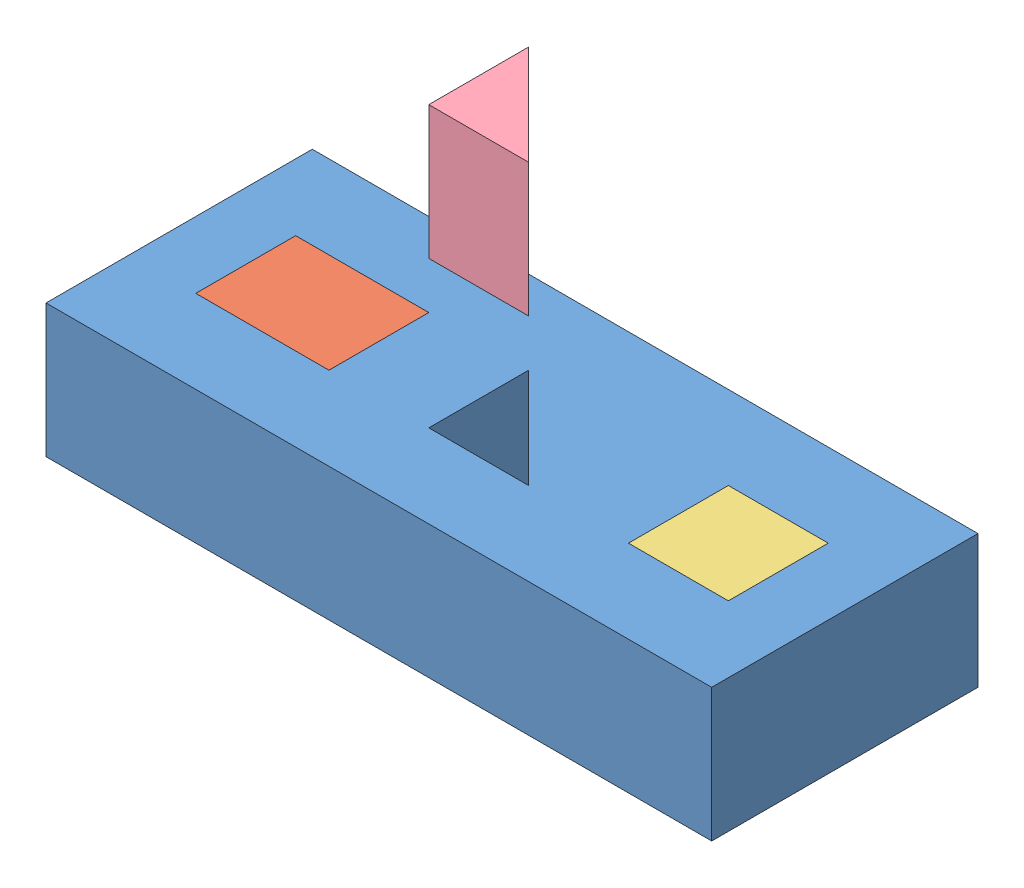
SolidWorks assembly Assembly 61, configuration Default. Lengths in mm.
Overall size (127 78.8 50.8).
4 component instances, 4 part files, 8 mates.
Components (placement in the parent):
- Block_Coinc_parallel_prepend_2013-2: Block_Coinc_parallel_prepend_2013 [Default] at (-15.2145 52.4167 123.2064) size (127 25.4 50.8)
- rectangle_1_2013-2: rectangle_1_2013 [Default] at (-2.5145 52.4167 107.3314) size (25.4 25.4 19.05)
- Square_2013-2: Square_2013 [Default] at (80.0355 52.4167 107.3314) size (19.05 25.4 19.05)
- Traingle_2013-2: Traingle_2013 [Default] at (41.9355 105.8179 107.3314) size (19.05 25.4 19.05)
Mates (geometry in assembly coordinates):
- Coincident11: coincident: point of Block_Coinc_parallel_prepend_2013-2; point of rectangle_1_2013-2
- Coincident12: coincident: point of Block_Coinc_parallel_prepend_2013-2; point of rectangle_1_2013-2
- Coincident13: coincident aligned: plane of Block_Coinc_parallel_prepend_2013-2 through (-15.2145 77.8167 123.2064) normal (0 1 0); plane of rectangle_1_2013-2 through (-2.5145 77.8167 107.3314) normal (0 1 0)
- Perpendicular2: perpendicular: plane of Block_Coinc_parallel_prepend_2013-2 through (41.9355 52.4167 88.2814) normal (1 0 0); plane of Traingle_2013-2 through (41.9355 77.8167 107.3314) normal (0 0 1)
- Coincident15: coincident anti-aligned: line of Block_Coinc_parallel_prepend_2013-2 through (60.9855 52.4167 107.3314) axis (0 1 0); line of Traingle_2013-2 through (60.9855 77.8167 107.3314) axis (0 -1 0)
- Coincident17: coincident anti-aligned: plane of Block_Coinc_parallel_prepend_2013-2 through (80.0355 52.4167 107.3314) normal (0 0 -1); plane of Square_2013-2 through (80.0355 77.8167 107.3314) normal (0 0 1)
- Coincident18: coincident anti-aligned: plane of Block_Coinc_parallel_prepend_2013-2 through (99.0855 52.4167 107.3314) normal (-1 0 0); plane of Square_2013-2 through (99.0855 77.8167 107.3314) normal (1 0 0)
- Coincident19: coincident aligned: plane of Block_Coinc_parallel_prepend_2013-2 through (-15.2145 77.8167 123.2064) normal (0 1 0); plane of Square_2013-2 through (80.0355 77.8167 107.3314) normal (0 1 0)
